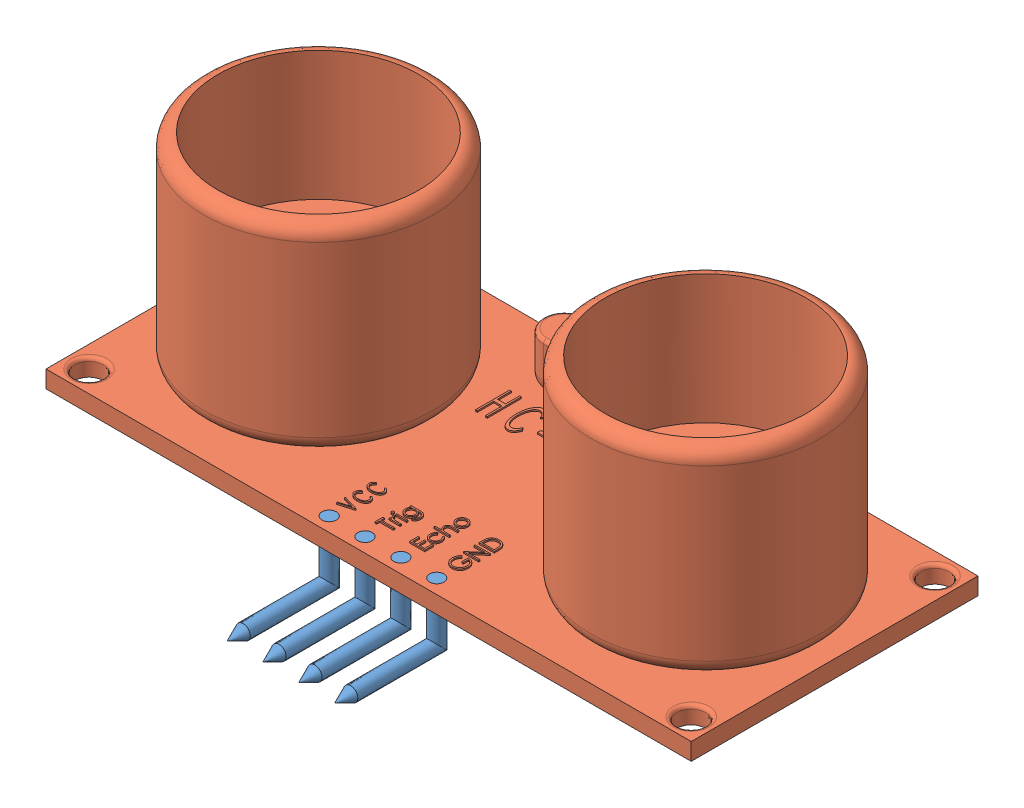
SolidWorks assembly ultra_sonic, configuration Défaut. Lengths in mm.
Overall size (45 18.3 26.12).
7 component instances, 3 part files, 0 mates.
Components (placement in the parent):
- pin header-1: pin header [Défaut] at (-4.1109 -10.7267 50.9724) x (0 0 -1) z (1 0 0) size (7.62 4.5 1)
- UltraSonic-1: UltraSonic [Défaut] at (-2.8609 -7.9267 1.7996) size (45 15 20)
- pin header-2: pin header [Défaut] at (0.8891 -10.7267 50.9724) x (0 0 -1) z (1 0 0) size (7.62 4.5 1)
- part2-1: part2 [Défaut] at (-16.3609 -2.9267 1.7996) x (0.862539 0 -0.505991) z (0.505991 0 0.862539) size (8 0.65 8)
- pin header-3: pin header [Défaut] at (-6.6109 -10.7267 50.9724) x (0 0 -1) z (1 0 0) size (7.62 4.5 1)
- pin header-4: pin header [Défaut] at (-1.6109 -10.7267 50.9724) x (0 0 -1) z (1 0 0) size (7.62 4.5 1)
- part2-2: part2 [Défaut] at (10.6391 -2.6926 1.7996) x (0.988186 0 -0.153259) z (0.153259 0 0.988186) size (8 0.65 8)
